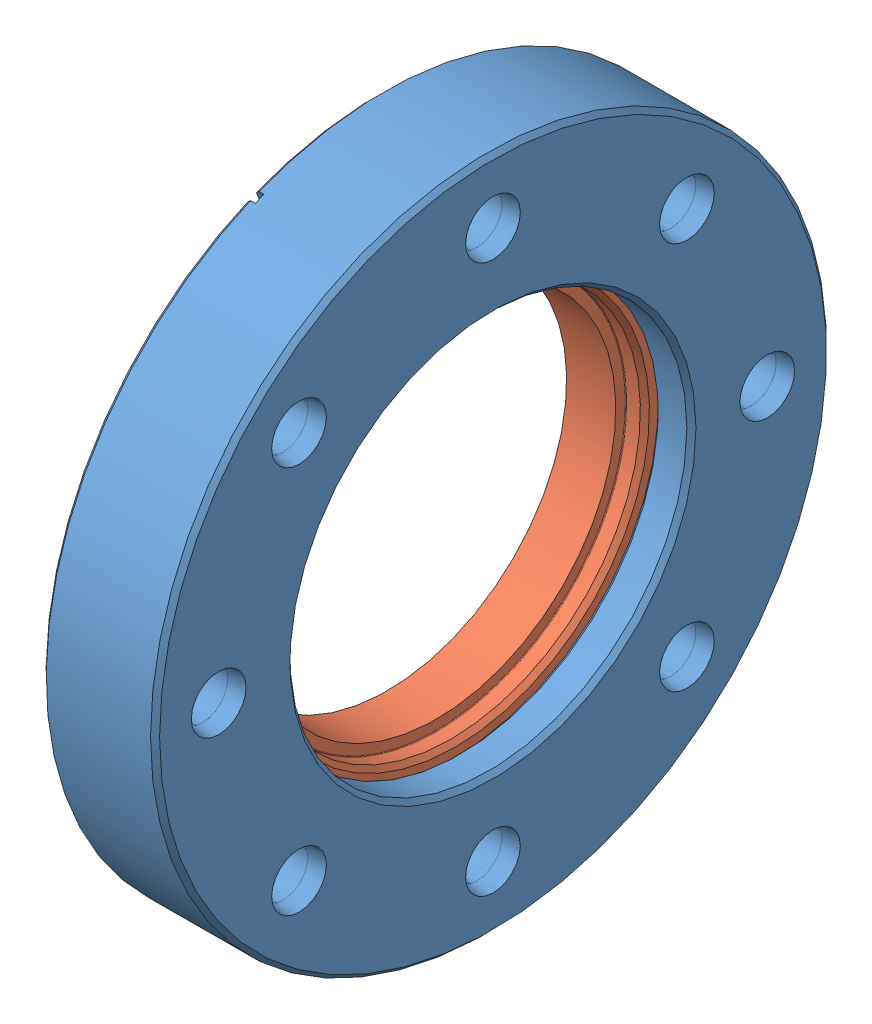
SolidWorks assembly 100021, configuration Default. Lengths in mm.
Overall size (19.06 113.54 113.54).
2 component instances, 2 part files, 2 mates.
Components (placement in the parent):
- 915004-1: 915004 [Default] at (22.0037 51.6024 98.0744) size (19.06 113.54 113.54)
- 910021-1: 910021 [Default] at (22.6641 51.6024 98.0744) x (1 0 0) z (0 -0.029371 0.999569) size (11.99 82.32 82.32)
Mates (geometry in assembly coordinates):
- Concentric1: concentric: cylinder of 915004-1 through (22.0037 51.6024 98.0744) axis (-1 0 0) radius 56.769; cylinder of 910021-1 through (22.6641 51.6024 98.0744) axis (-1 0 0) radius 41.1607
- Coincident1: coincident anti-aligned: plane of 915004-1 through (34.7037 92.8774 98.0744) normal (-1 0 0); plane of 910021-1 through (34.7037 92.7454 99.2833) normal (1 0 0)
